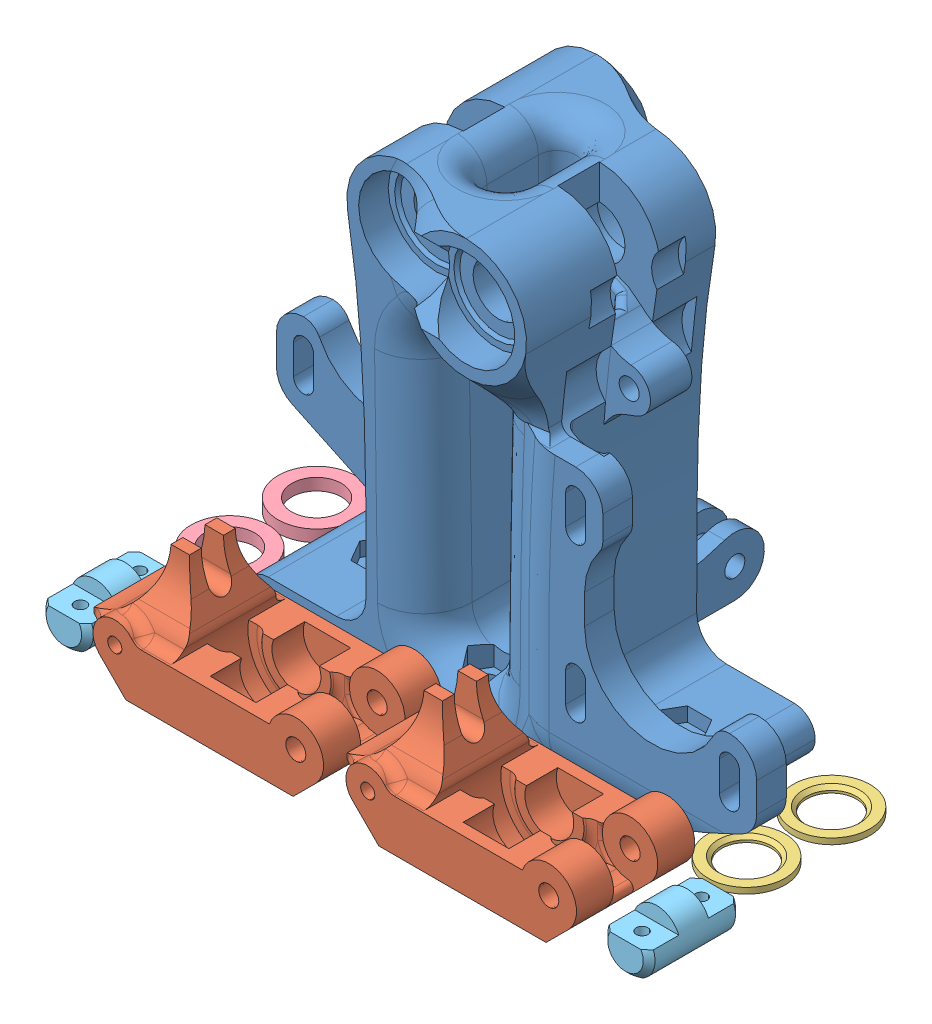
SolidWorks assembly IttyBittyDoublePlate2, configuration 3mm. Lengths in mm.
Overall size (185 79.3 185).
9 component instances, 5 part files, 13 mates.
Components (placement in the parent):
- IttyBittyDoubleExtruderBlock-1: IttyBittyDoubleExtruderBlock [Default] at (0 4.6 0)
- IdlerBlock-1: IdlerBlock [Default] at (-15.8961 7.6 26.518) x (0 1 0) z (0 0 1)
- IdlerBlock-2: IdlerBlock [Default] at (26.8647 7.6 26.518) x (0 1 0) z (0 0 1)
- Spacer 1mm-1: Spacer 1mm [Default] at (43.7366 0 -7.0068) x (1 0 0) z (0 1 0)
- Spacer 2mm-1: Spacer 2mm [Default] at (-44.1346 0 6.8687) x (1 0 0) z (0 1 0)
- Spacer 1mm-2: Spacer 1mm [Default] at (43.7964 0 7.4079) x (1 0 0) z (0 1 0)
- Spacer 2mm-2: Spacer 2mm [Default] at (-44.0155 0 -7.7189) x (1 0 0) z (0 1 0)
- IdlerPin-15mm-1: IdlerPin-15mm [Default] at (-45.2785 3.5 25.945) x (0 1 0) z (0 0 1)
- IdlerPin-15mm-2: IdlerPin-15mm [Default] at (49.9545 3.5 26.2329) x (0 1 0) z (0 0 1)
Mates (geometry in assembly coordinates):
- Coincident1: coincident aligned: plane of IttyBittyDoubleExtruderBlock-1 through (0 4.6 0) normal (0 0 1); plane of assembly through (0 0 0) normal (0 0 1)
- Coincident3: coincident aligned: plane of IttyBittyDoubleExtruderBlock-1 through (0 4.6 0) normal (1 0 0); plane of assembly through (0 0 0) normal (1 0 0)
- Coincident5: coincident anti-aligned: plane of IttyBittyDoubleExtruderBlock-1 through (0 0 0) normal (0 -1 0); plane of assembly through (0 0 0) normal (0 1 0)
- Coincident6: coincident anti-aligned: plane of IdlerBlock-1 through (-15.8961 0 16.518) normal (0 -1 0); plane of assembly through (0 0 0) normal (0 1 0)
- Coincident9: coincident anti-aligned: plane of Spacer 2mm-1 through (-44.1346 0 6.8687) normal (0 -1 0); plane of assembly through (0 0 0) normal (0 1 0)
- Coincident10: coincident anti-aligned: plane of Spacer 1mm-1 through (43.7366 0 -7.0068) normal (0 -1 0); plane of assembly through (0 0 0) normal (0 1 0)
- Coincident12: coincident aligned: plane of IttyBittyDoubleExtruderBlock-1 through (0 0 0) normal (0 -1 0); plane of Spacer 2mm-1 through (-44.1346 0 6.8687) normal (0 -1 0)
- Coincident13: coincident aligned: plane of IttyBittyDoubleExtruderBlock-1 through (0 0 0) normal (0 -1 0); plane of Spacer 2mm-2 through (-44.0155 0 -7.7189) normal (0 -1 0)
- Coincident16: coincident aligned: plane of IttyBittyDoubleExtruderBlock-1 through (0 0 0) normal (0 -1 0); plane of Spacer 1mm-2 through (43.7964 0 7.4079) normal (0 -1 0)
- Coincident17: coincident aligned: plane of IttyBittyDoubleExtruderBlock-1 through (0 0 0) normal (0 -1 0); plane of IdlerBlock-2 through (26.8647 0 16.518) normal (0 -1 0)
- Coincident18: coincident anti-aligned: plane of IdlerPin-15mm-1 through (-45.2785 0 18.145) normal (0 -1 0); plane of assembly through (0 0 0) normal (0 1 0)
- Coincident19: coincident anti-aligned: plane of IdlerPin-15mm-2 through (49.9545 0 18.4329) normal (0 -1 0); plane of assembly through (0 0 0) normal (0 1 0)
- Coincident20: coincident aligned: plane of IdlerBlock-1 through (-15.8961 7.6 36.518) normal (0 0 1); plane of IdlerBlock-2 through (26.8647 7.6 36.518) normal (0 0 1)
